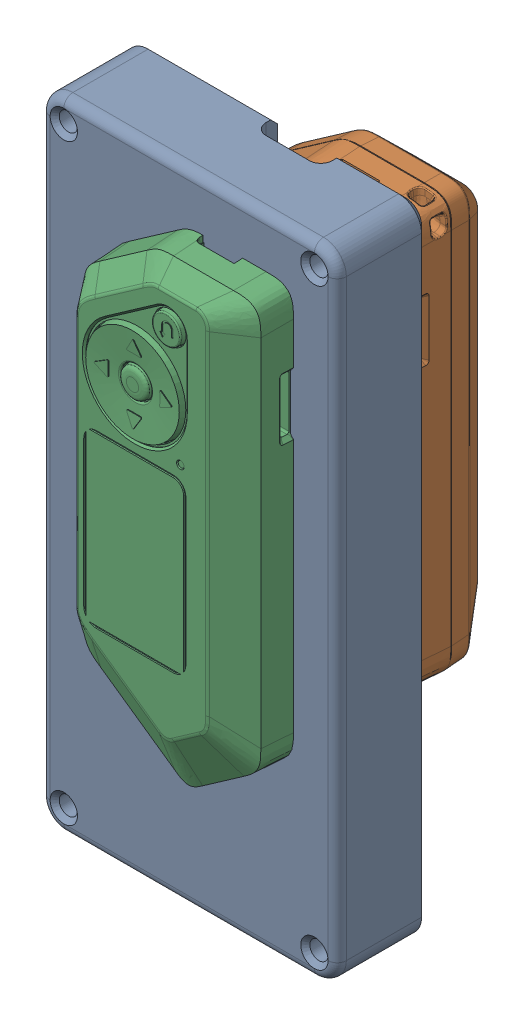
SolidWorks assembly initial assembly (need to improve), configuration Assem1. Lengths in mm.
Overall size (65 120 40.55).
2 component instances, 2 part files, 2 mates.
Components (placement in the parent):
- Shell V2-1: Shell V2 [Part6] at origin size (65 140 43.01)
- Flipper imported geo-1: Flipper imported geo [Part5] at (-0.0689 0.3793 29) x (1 0 0) z (0 0 1) size (40.45 100.96 25.61) (hidden)
Mates (geometry in assembly coordinates):
- Distance1: distance = 1 mm: plane of Shell V1-1 through (-44.2415 86.3292 5) normal (0 0 1); plane of Flipper imported geo-1 through (-11.6059 32.5374 6) normal (0 0 -1)
- Distance2: distance = 16 mm: plane of Flipper imported geo-1 through (-12.2762 74.2789 20.7494) normal (0 1 0); line of Shell V1-1 through (-5.3409 90.2789 15) axis (-1 0 0)
